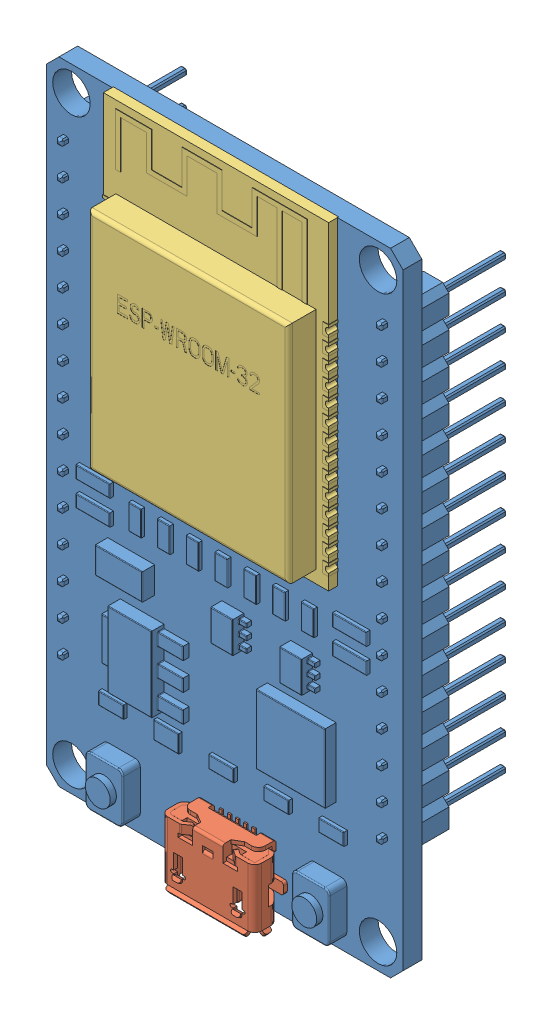
SolidWorks assembly ESP-32_v1, configuration Predeterminado. Lengths in mm.
Overall size (28.5 50.93 12.4).
3 component instances, 3 part files, 6 mates.
Components (placement in the parent):
- 6.ESP-32-1: 6.ESP-32 [Predeterminado] at (-6.3746 -6.0494 52.8) x (1 0 0) z (0 -1 0) size (28.5 11.4 50.5)
- micro_usb_47346-0001-1: micro_usb_47346-0001 [Default] at (-5.2796 -28.9494 55.525) x (1 0 0) z (0 -1 0) size (7.98 2.94 5.43)
- KiCAD-ESP-WROOM-32-1: KiCAD-ESP-WROOM-32 [Predeterminado] at (-7.4715 7.074 53.6914) x (-1 0 0) z (0 0 1) size (18.07 25.54 3.04)
Mates (geometry in assembly coordinates):
- Coincident1: coincident anti-aligned: plane of 6.ESP-32-1 through (-6.3746 -6.0494 54.2) normal (0 0 1); plane of KiCAD-ESP-WROOM-32-1 through (-15.3746 -6.2994 54.2) normal (0 0 -1)
- Coincident2: coincident anti-aligned: plane of 6.ESP-32-1 through (2.6254 19.2006 54.2) normal (-1 0 0); plane of KiCAD-ESP-WROOM-32-1 through (2.6254 11.9506 54.2) normal (1 0 0)
- Coincident3: coincident anti-aligned: plane of 6.ESP-32-1 through (-15.3746 -6.2994 54.2) normal (0 1 0); plane of KiCAD-ESP-WROOM-32-1 through (-15.3746 -6.2994 54.2) normal (0 -1 0)
- Coincident4: coincident anti-aligned: plane of 6.ESP-32-1 through (-6.3746 -6.0494 54.4) normal (0 0 1); plane of micro_usb_47346-0001-1 through (-4.4696 -28.4127 54.4) normal (0 0 -1)
- Coincident5: coincident anti-aligned: plane of 6.ESP-32-1 through (-6.3746 -30.9494 54.4) normal (0 -1 0); plane of micro_usb_47346-0001-1 through (-5.2796 -30.9494 55.525) normal (0 1 0)
- Coincident6: coincident anti-aligned: plane of 6.ESP-32-1 through (-3.7796 -6.0494 54.4) normal (1 0 0); plane of micro_usb_47346-0001-1 through (-3.7796 -28.9494 55.525) normal (-1 0 0)
